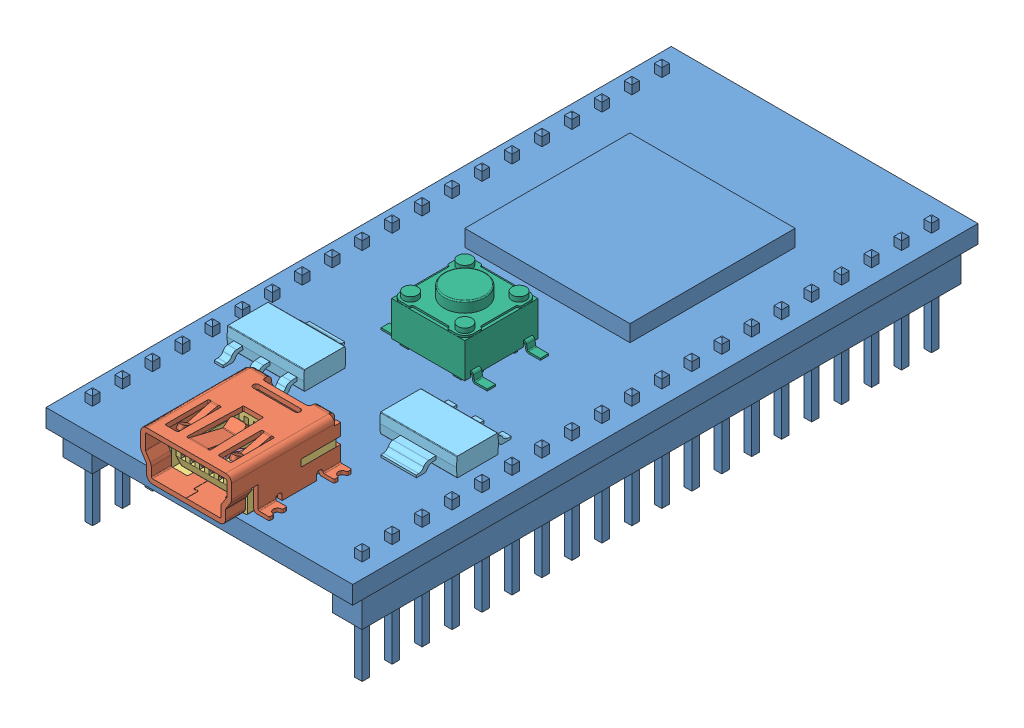
SolidWorks assembly mbed_NXP_LPC1768, configuration Default. Lengths in mm.
Overall size (26 13.32 54.13).
12 component instances, 6 part files, 15 mates.
Components (placement in the parent):
- mbed_NXP_LPC1768-1: mbed_NXP_LPC1768 [Default] at origin size (26 10.42 53)
- usb_mini_b-1: usb_mini_b [Default] at (0 3.474 23) x (-1 0 0) z (0 -1 0) size (9.6 9.25 4.91)
  - Shielding-1: Shielding [Default] at origin size (9.6 9.25 4.01)
  - Insulator-1: Insulator [Default] at (0 2.75 0.2) size (7.7 7.5 4.5)
  - Pin_1-1: Pin_1 [Default] at (-1.6 2.225 0.575) size (0.4 7.85 3.02)
  - Pin_1-2: Pin_1 [Default] at (-0.8 2.225 0.575) size (0.4 7.85 3.02)
  - Pin_1-3: Pin_1 [Default] at (0 2.225 0.575) size (0.4 7.85 3.02)
  - Pin_1-4: Pin_1 [Default] at (0.8 2.225 0.575) size (0.4 7.85 3.02)
  - Pin_1-5: Pin_1 [Default] at (1.6 2.225 0.575) size (0.4 7.85 3.02)
- SOT-223-1: SOT-223 [Default] at (-6.8 -6.9808 24) x (0 0 1) z (-1 0 0) size (6.89 1.7 6.5)
- SOT-223-2: SOT-223 [Default] at (6.7 -6.9808 1.2) x (0 0 -1) z (1 0 0) size (6.89 1.7 6.5)
- Tact_Sw_SMD_6x6mm-1: Tact_Sw_SMD_6x6mm [Default] at (0 1.524 4) x (1 0 0) z (0 1 0) size (9 6.2 4.3)
Mates (geometry in assembly coordinates):
- Coincident1: coincident aligned: plane of mbed_NXP_LPC1768-1 through (0 0 0) normal (0 0 1); plane of assembly through (0 0 0) normal (0 0 1)
- Coincident2: coincident aligned: plane of mbed_NXP_LPC1768-1 through (0 0 0) normal (0 1 0); plane of assembly through (0 0 0) normal (0 1 0)
- Coincident3: coincident aligned: plane of mbed_NXP_LPC1768-1 through (0 0 0) normal (1 0 0); plane of assembly through (0 0 0) normal (1 0 0)
- Coincident4: coincident anti-aligned: plane of mbed_NXP_LPC1768-1 through (0 1.524 0) normal (0 1 0); plane of usb_mini_b-1/Insulator-1 through (-3.45 1.524 21.725) normal (0 -1 0)
- Coincident6: coincident anti-aligned: plane of usb_mini_b-1/Shielding-1; plane of assembly through (0 0 0) normal (1 0 0)
- Distance2: distance = 23 mm anti-aligned: plane of assembly through (0 0 0) normal (0 0 1); plane of usb_mini_b-1/Shielding-1
- Coincident9: coincident anti-aligned: plane of mbed_NXP_LPC1768-1 through (0 1.524 0) normal (0 1 0); plane of SOT-223-1 through (-9.7114 1.524 10.9319) normal (0 -1 0)
- Coincident10: coincident anti-aligned: plane of mbed_NXP_LPC1768-1 through (0 1.524 0) normal (0 1 0); plane of SOT-223-2 through (9.6114 1.524 14.2681) normal (0 -1 0)
- Distance3: distance = 6.8 mm anti-aligned: plane of SOT-223-1 through (-6.8 -6.9808 24) normal (-1 0 0); plane of assembly through (0 0 0) normal (1 0 0)
- Distance4: distance = 6.7 mm aligned: plane of assembly through (0 0 0) normal (1 0 0); plane of SOT-223-2 through (6.7 -6.9808 1.2) normal (1 0 0)
- Distance5: distance = 1.2 mm anti-aligned: plane of SOT-223-2 through (6.7 -6.9808 1.2) normal (0 0 -1); plane of assembly through (0 0 0) normal (0 0 1)
- Distance6: distance = 24 mm aligned: plane of assembly through (0 0 0) normal (0 0 1); plane of SOT-223-1 through (-6.8 -6.9808 24) normal (0 0 1)
- Coincident15: coincident anti-aligned: plane of mbed_NXP_LPC1768-1 through (0 1.524 0) normal (0 1 0); plane of Tact_Sw_SMD_6x6mm-1 through (-3.492 1.524 2.8445) normal (0 -1 0)
- Coincident16: coincident aligned: plane of Tact_Sw_SMD_6x6mm-1; plane of assembly
- Distance7: distance = 4 mm anti-aligned: plane of assembly; plane of Tact_Sw_SMD_6x6mm-1 through (0 1.524 4) normal (0 0 -1)
